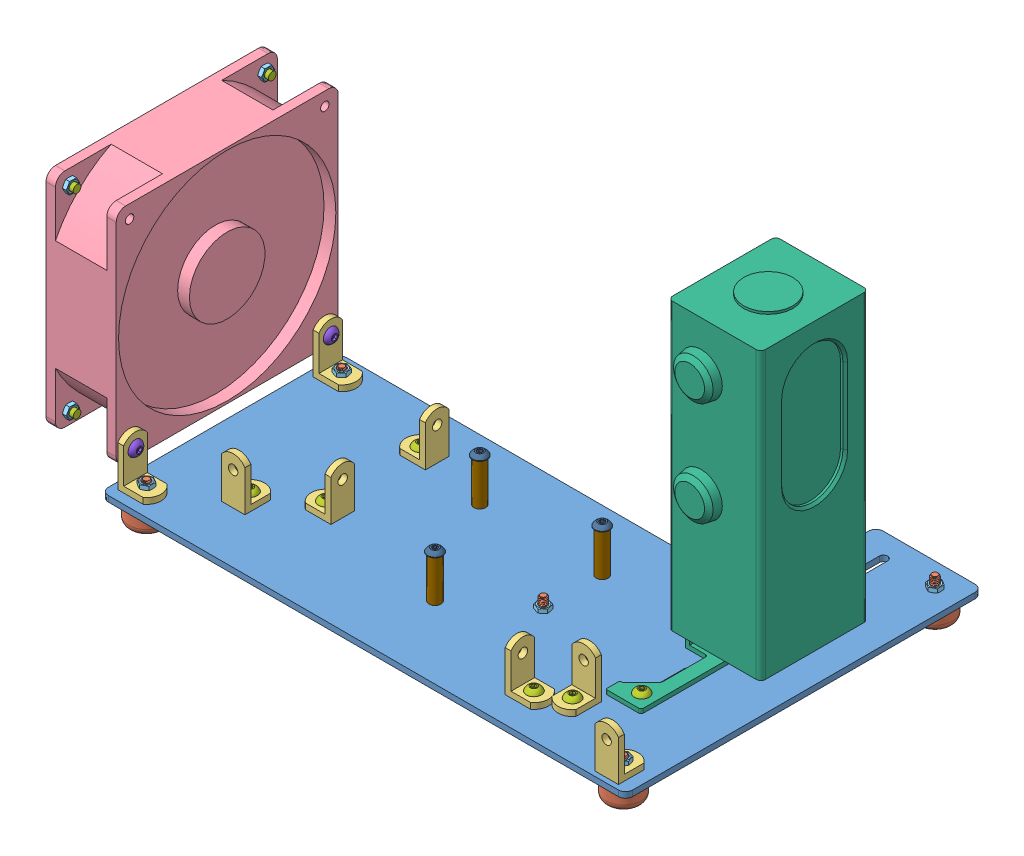
SolidWorks assembly Chiller Plate, configuration Default. Lengths in mm.
Overall size (343.32 202.03 208.02).
58 component instances, 10 part files, 114 mates.
Components (placement in the parent):
- Chiller base plate-1: Chiller base plate [Default] at (-211.7096 17.6388 83.7447) size (281.94 3.07 191.77)
- RUBBER_BUMPER WITH 8-32x375 THREADED STUD-1: RUBBER_BUMPER WITH 8-32x375 THREADED STUD [9541K2] at (-199.0096 17.6388 72.1097) x (-0.837169 0 -0.546944) z (-0.546944 0 0.837169) size (19.05 20.95 19.05)
- RUBBER_BUMPER WITH 8-32x375 THREADED STUD-2: RUBBER_BUMPER WITH 8-32x375 THREADED STUD [9541K2] at (-199.0096 17.6388 -32.8903) x (-0.925243 0 -0.379375) z (-0.379375 0 0.925243) size (19.05 20.95 19.05)
- RUBBER_BUMPER WITH 8-32x375 THREADED STUD-3: RUBBER_BUMPER WITH 8-32x375 THREADED STUD [9541K2] at (57.5304 17.6388 72.1097) x (-0.985271 0 -0.170998) z (-0.170998 0 0.985271) size (19.05 20.95 19.05)
- RUBBER_BUMPER WITH 8-32x375 THREADED STUD-4: RUBBER_BUMPER WITH 8-32x375 THREADED STUD [9541K2] at (57.5304 17.6388 -95.3253) x (-0.997902 0 0.064746) z (0.064746 0 0.997902) size (19.05 20.95 19.05)
- l-bracket_correct-1: l-bracket_correct [Default] at (-208.1028 41.2316 52.9979) x (0 0 -1) z (0 -1 0) size (12.7 16.94 25.35)
- l-bracket_correct-2: l-bracket_correct [Default] at (-208.1028 41.2316 -52.0021) x (0 0 -1) z (0 -1 0) size (12.7 16.94 25.35)
- 120mm_fan-2: 120mm_fan [Default] at (-208.1028 148.004 70.9708) x (0 1 0) z (0 0 1) size (119.38 37.75 119.38)
- S-008-NUT-SS-001_832-SS-Nut-3-32thk-1: S-008-NUT-SS-001_832-SS-Nut-3-32thk [Default] at (-199.0096 23.8872 72.1097) size (6.35 2.38 7.33)
- S-008-NUT-SS-001_832-SS-Nut-3-32thk-2: S-008-NUT-SS-001_832-SS-Nut-3-32thk [Default] at (-199.0096 23.8872 -32.8903) x (0.982082 0 -0.188455) z (0.188455 0 0.982082) size (6.35 2.38 7.33)
- S-008-NUT-SS-001_832-SS-Nut-3-32thk-4: S-008-NUT-SS-001_832-SS-Nut-3-32thk [Default] at (57.5304 20.7122 72.1097) x (0.918365 0 -0.395734) z (0.395734 0 0.918365) size (6.35 2.38 7.33)
- l-bracket_correct-7: l-bracket_correct [Default] at (-8.4588 41.2316 44.3129) x (0 0 -1) z (0 -1 0) size (12.7 16.94 25.35)
- l-bracket_correct-8: l-bracket_correct [Default] at (38.4186 41.2316 81.2029) x (-1 0 0) z (0 -1 0) size (12.7 16.94 25.35)
- S-008-NUT-SS-001_832-SS-Nut-3-32thk-5: S-008-NUT-SS-001_832-SS-Nut-3-32thk [Default] at (57.5304 20.7122 -95.3253) size (6.35 2.38 7.33)
- S-008-NUT-SS-001_832-SS-Nut-3-32thk-6: S-008-NUT-SS-001_832-SS-Nut-3-32thk [Default] at (57.5304 23.8872 72.1097) x (0.965281 0 -0.261214) z (0.261214 0 0.965281) size (6.35 2.38 7.33)
- SamsungFoodChiller-1: SamsungFoodChiller [Default] at (-59.6355 20.7122 23.7904) (suppressed, hidden)
- Pump_Reservoir-1: Pump_Reservoir [Default] at (45.3708 36.5618 -17.865) x (0 0 -1) z (1 0 0) size (120.7 170.79 61.26)
- S-008-038-BTN-H-SS-001-832x3_8-button-head-screw-1: S-008-038-BTN-H-SS-001-832x3_8-button-head-screw [Default] at (29.8444 23.0236 -70.365) size (7.92 11.73 7.92)
- S-008-NUT-SS-001_832-SS-Nut-3-32thk-7: S-008-NUT-SS-001_832-SS-Nut-3-32thk [Default] at (29.8444 15.2575 -70.365) size (6.35 2.38 7.33)
- S-008-038-BTN-H-SS-001-832x3_8-button-head-screw-2: S-008-038-BTN-H-SS-001-832x3_8-button-head-screw [Default] at (29.8444 23.0236 34.635) x (0.982082 0 -0.188455) z (0.188455 0 0.982082) size (7.92 11.73 7.92)
- S-008-NUT-SS-001_832-SS-Nut-3-32thk-8: S-008-NUT-SS-001_832-SS-Nut-3-32thk [Default] at (29.8444 15.2575 34.635) x (0.982082 0 -0.188455) z (0.188455 0 0.982082) size (6.35 2.38 7.33)
- S-008-050-BTN-H-SS-001-832x1_2-button-head-screw-1: S-008-050-BTN-H-SS-001-832x1_2-button-head-screw [Default] at (-204.9278 38.4922 72.1097) x (0 -1 0) z (0 0 1) size (7.92 14.91 7.92)
- S-008-NUT-SS-001_832-SS-Nut-3-32thk-11: S-008-NUT-SS-001_832-SS-Nut-3-32thk [Default] at (-215.5591 38.4922 72.1097) x (0 -0.930301 -0.366796) z (0 -0.366796 0.930301) size (6.35 2.38 7.33)
- S-008-050-BTN-H-SS-001-832x1_2-button-head-screw-2: S-008-050-BTN-H-SS-001-832x1_2-button-head-screw [Default] at (-204.9278 38.4922 -32.8903) x (0 -0.987351 -0.158553) z (0 -0.158553 0.987351) size (7.92 14.91 7.92)
- S-008-NUT-SS-001_832-SS-Nut-3-32thk-13: S-008-NUT-SS-001_832-SS-Nut-3-32thk [Default] at (-215.5591 38.4922 -32.8903) x (0 -0.860377 -0.509658) z (0 -0.509658 0.860377) size (6.35 2.38 7.33)
- RUBBER_BUMPER WITH 8-32x375 THREADED STUD-6: RUBBER_BUMPER WITH 8-32x375 THREADED STUD [9541K2] at (-38.1482 17.6388 19.6097) x (-0.985271 0 -0.170998) z (-0.170998 0 0.985271) size (19.05 20.95 19.05)
- S-008-NUT-SS-001_832-SS-Nut-3-32thk-16: S-008-NUT-SS-001_832-SS-Nut-3-32thk [Default] at (-38.1482 20.7122 19.6097) x (0.309274 0 -0.950973) z (0.950973 0 0.309274) size (6.35 2.38 7.33)
- 008 875ALUM UNTHRD SPACER-2: 008 875ALUM UNTHRD SPACER [92510A468] at (-103.9661 31.8247 -12.0903) x (1 0 0) z (0 -1 0) size (6.35 6.35 22.23)
- 008 875ALUM UNTHRD SPACER-3: 008 875ALUM UNTHRD SPACER [92510A468] at (-38.1482 31.8247 -12.0903) x (1 0 0) z (0 -1 0) size (6.35 6.35 22.23)
- 008 875ALUM UNTHRD SPACER-4: 008 875ALUM UNTHRD SPACER [92510A468] at (-71.0571 31.8247 44.9097) x (1 0 0) z (0 -1 0) size (6.35 6.35 22.23)
- S-008-1125-STD-O-AL-001_832xp1125_standoff_p1125hex-1: S-008-1125-STD-O-AL-001_832xp1125_standoff_p1125hex [92949A820] at (-103.9661 45.622 -12.0903) x (1 0 0) z (0 1 0) size (7.92 7.92 31.31)
- S-008-1125-STD-O-AL-001_832xp1125_standoff_p1125hex-2: S-008-1125-STD-O-AL-001_832xp1125_standoff_p1125hex [92949A820] at (-38.1482 45.622 -12.0903) x (0.982082 0 -0.188455) z (0 1 0) size (7.92 7.92 31.31)
- S-008-1125-STD-O-AL-001_832xp1125_standoff_p1125hex-4: S-008-1125-STD-O-AL-001_832xp1125_standoff_p1125hex [92949A820] at (-71.0571 45.622 44.9097) x (0.918365 0 -0.395734) z (0 1 0) size (7.92 7.92 31.31)
- S-008-NUT-SS-001_832-SS-Nut-3-32thk-17: S-008-NUT-SS-001_832-SS-Nut-3-32thk [Default] at (-71.0571 17.6388 44.9097) x (-0.438446 0 0.898758) z (0.898758 0 0.438446) size (6.35 2.38 7.33)
- S-008-NUT-SS-001_832-SS-Nut-3-32thk-19: S-008-NUT-SS-001_832-SS-Nut-3-32thk [Default] at (-103.9661 17.6388 -12.0903) x (-0.621885 0 0.783109) z (0.783109 0 0.621885) size (6.35 2.38 7.33)
- S-008-NUT-SS-001_832-SS-Nut-3-32thk-21: S-008-NUT-SS-001_832-SS-Nut-3-32thk [Default] at (-38.1482 17.6388 -12.0903) x (-0.78814 0 0.615496) z (0.615496 0 0.78814) size (6.35 2.38 7.33)
- l-bracket_correct-9: l-bracket_correct [Default] at (-134.5444 41.2316 -0.6485) x (0 0 1) z (0 -1 0) size (12.7 16.94 25.35)
- l-bracket_correct-10: l-bracket_correct [Default] at (-134.5444 41.2316 50.1515) x (0 0 1) z (0 -1 0) size (12.7 16.94 25.35)
- l-bracket_correct-12: l-bracket_correct [Default] at (-187.6414 41.2316 56.0079) x (-1 0 0) z (0 -1 0) size (12.7 16.94 25.35)
- l-bracket_correct-14: l-bracket_correct [Default] at (33.4622 41.2316 47.2195) x (1 0 0) z (0 -1 0) size (12.7 16.94 25.35)
- S-008-038-BTN-H-SS-001-832x3_8-button-head-screw-4: S-008-038-BTN-H-SS-001-832x3_8-button-head-screw [Default] at (-245.8528 143.4922 -32.8903) x (0 1 0) z (0 0 1) size (7.92 11.73 7.92)
- S-008-NUT-SS-001_832-SS-Nut-3-32thk-22: S-008-NUT-SS-001_832-SS-Nut-3-32thk [Default] at (-238.3966 143.4922 -32.8903) x (0 1 0) z (0 0 1) size (6.35 2.38 7.33)
- S-008-038-BTN-H-SS-001-832x3_8-button-head-screw-5: S-008-038-BTN-H-SS-001-832x3_8-button-head-screw [Default] at (-245.8528 38.4922 -32.8903) x (0 1 0) z (0 0 1) size (7.92 11.73 7.92)
- S-008-038-BTN-H-SS-001-832x3_8-button-head-screw-6: S-008-038-BTN-H-SS-001-832x3_8-button-head-screw [Default] at (-245.8528 143.4922 72.1097) x (0 1 0) z (0 0 1) size (7.92 11.73 7.92)
- S-008-038-BTN-H-SS-001-832x3_8-button-head-screw-7: S-008-038-BTN-H-SS-001-832x3_8-button-head-screw [Default] at (-245.8528 38.4922 72.1097) x (0 1 0) z (0 0 1) size (7.92 11.73 7.92)
- S-008-NUT-SS-001_832-SS-Nut-3-32thk-23: S-008-NUT-SS-001_832-SS-Nut-3-32thk [Default] at (-238.3966 38.4922 -32.8903) x (0 1 0) z (0 0 1) size (6.35 2.38 7.33)
- S-008-NUT-SS-001_832-SS-Nut-3-32thk-24: S-008-NUT-SS-001_832-SS-Nut-3-32thk [Default] at (-238.3966 143.4922 72.1097) x (0 1 0) z (0 0 1) size (6.35 2.38 7.33)
- S-008-NUT-SS-001_832-SS-Nut-3-32thk-25: S-008-NUT-SS-001_832-SS-Nut-3-32thk [Default] at (-238.3966 38.4922 72.1097) x (0 1 0) z (0 0 1) size (6.35 2.38 7.33)
- S-008-038-BTN-H-SS-001-832x3_8-button-head-screw-8: S-008-038-BTN-H-SS-001-832x3_8-button-head-screw [Default] at (-143.6376 23.8872 31.0397) size (7.92 11.73 7.92)
- S-008-NUT-SS-001_832-SS-Nut-3-32thk-26: S-008-NUT-SS-001_832-SS-Nut-3-32thk [Default] at (-143.6376 15.2575 31.0397) size (6.35 2.38 7.33)
- S-008-038-BTN-H-SS-001-832x3_8-button-head-screw-9: S-008-038-BTN-H-SS-001-832x3_8-button-head-screw [Default] at (-168.5296 23.8872 46.9147) x (0.982082 0 -0.188455) z (0.188455 0 0.982082) size (7.92 11.73 7.92)
- S-008-NUT-SS-001_832-SS-Nut-3-32thk-27: S-008-NUT-SS-001_832-SS-Nut-3-32thk [Default] at (-168.5296 15.2575 46.9147) x (0.982082 0 -0.188455) z (0.188455 0 0.982082) size (6.35 2.38 7.33)
- S-008-038-BTN-H-SS-001-832x3_8-button-head-screw-10: S-008-038-BTN-H-SS-001-832x3_8-button-head-screw [Default] at (-143.6376 23.8872 -19.7603) x (0.918365 0 -0.395734) z (0.395734 0 0.918365) size (7.92 11.73 7.92)
- S-008-NUT-SS-001_832-SS-Nut-3-32thk-29: S-008-NUT-SS-001_832-SS-Nut-3-32thk [Default] at (-143.6376 15.2575 -19.7603) x (0.918365 0 -0.395734) z (0.395734 0 0.918365) size (6.35 2.38 7.33)
- S-008-038-BTN-H-SS-001-832x3_8-button-head-screw-11: S-008-038-BTN-H-SS-001-832x3_8-button-head-screw [Default] at (0.6344 23.8872 63.4247) x (0.8 0 -0.6) z (0.6 0 0.8) size (7.92 11.73 7.92)
- S-008-NUT-SS-001_832-SS-Nut-3-32thk-31: S-008-NUT-SS-001_832-SS-Nut-3-32thk [Default] at (0.6344 15.2575 63.4247) x (0.8 0 -0.6) z (0.6 0 0.8) size (6.35 2.38 7.33)
- S-008-038-BTN-H-SS-001-832x3_8-button-head-screw-12: S-008-038-BTN-H-SS-001-832x3_8-button-head-screw [Default] at (14.3504 23.8872 56.3127) x (0.63358 0 -0.773678) z (0.773678 0 0.63358) size (7.92 11.73 7.92)
- S-008-NUT-SS-001_832-SS-Nut-3-32thk-33: S-008-NUT-SS-001_832-SS-Nut-3-32thk [Default] at (14.3504 15.2575 56.3127) x (0.63358 0 -0.773678) z (0.773678 0 0.63358) size (6.35 2.38 7.33)
Mates (geometry in assembly coordinates):
- Coincident1: coincident anti-aligned: plane of Chiller base plate-1 through (-211.7096 17.6388 83.7447) normal (0 -1 0); plane of RUBBER_BUMPER WITH 8-32x375 THREADED STUD-1 through (-204.9069 17.6388 68.2569) normal (0 1 0)
- Concentric1: concentric anti-aligned: cylinder of Chiller base plate-1 through (-199.0096 20.7122 72.1097) axis (0 1 0) radius 2.2479; circle of RUBBER_BUMPER WITH 8-32x375 THREADED STUD-1
- Coincident2: coincident anti-aligned: plane of Chiller base plate-1 through (-211.7096 17.6388 83.7447) normal (0 -1 0); plane of RUBBER_BUMPER WITH 8-32x375 THREADED STUD-2 through (-205.5273 17.6388 -35.5627) normal (0 1 0)
- Concentric2: concentric anti-aligned: cylinder of Chiller base plate-1 through (-199.0096 20.7122 -32.8903) axis (0 1 0) radius 2.2479; circle of RUBBER_BUMPER WITH 8-32x375 THREADED STUD-2
- Coincident3: coincident anti-aligned: plane of Chiller base plate-1 through (-211.7096 17.6388 83.7447) normal (0 -1 0); plane of RUBBER_BUMPER WITH 8-32x375 THREADED STUD-3 through (50.5899 17.6388 70.9051) normal (0 1 0)
- Concentric3: concentric anti-aligned: cylinder of Chiller base plate-1 through (57.5304 20.7122 72.1097) axis (0 1 0) radius 2.2479; circle of RUBBER_BUMPER WITH 8-32x375 THREADED STUD-3
- Coincident4: coincident anti-aligned: plane of Chiller base plate-1 through (-211.7096 17.6388 83.7447) normal (0 -1 0); plane of RUBBER_BUMPER WITH 8-32x375 THREADED STUD-4 through (50.5009 17.6388 -94.8692) normal (0 1 0)
- Concentric4: concentric anti-aligned: cylinder of Chiller base plate-1 through (57.5304 20.7122 -95.3253) axis (0 1 0) radius 2.2479; circle of RUBBER_BUMPER WITH 8-32x375 THREADED STUD-4
- Coincident6: coincident anti-aligned: plane of Chiller base plate-1 through (-211.7096 20.7122 83.7447) normal (0 1 0); plane of l-bracket_correct-1 through (-204.9278 20.7122 78.4597) normal (0 -1 0)
- Coincident7: coincident anti-aligned: plane of Chiller base plate-1 through (-211.7096 20.7122 83.7447) normal (0 1 0); plane of l-bracket_correct-2 through (-204.9278 20.7122 -26.5403) normal (0 -1 0)
- Concentric5: concentric aligned: circle of Chiller base plate-1; cylinder of l-bracket_correct-2 through (-199.0096 20.7122 -32.8903) axis (0 1 0) radius 2.54
- Concentric6: concentric aligned: circle of Chiller base plate-1; cylinder of l-bracket_correct-1 through (-199.0096 20.7122 72.1097) axis (0 1 0) radius 2.54
- Parallel1: parallel aligned: plane of Chiller base plate-1 through (-211.7096 20.7122 83.7447) normal (-1 0 0); plane of l-bracket_correct-1 through (-208.1028 41.2316 52.9979) normal (-1 0 0)
- Parallel2: parallel aligned: plane of Chiller base plate-1 through (-211.7096 20.7122 83.7447) normal (-1 0 0); plane of l-bracket_correct-2 through (-208.1028 41.2316 -52.0021) normal (-1 0 0)
- Concentric13: concentric anti-aligned: circle of l-bracket_correct-1; cylinder of S-008-NUT-SS-001_832-SS-Nut-3-32thk-1 through (-199.0096 26.2684 72.1097) axis (0 -1 0) radius 2.1828
- Coincident16: coincident anti-aligned: plane of l-bracket_correct-1 through (-191.1356 23.8872 78.4597) normal (0 1 0); plane of S-008-NUT-SS-001_832-SS-Nut-3-32thk-1 through (-199.0096 23.8872 72.1097) normal (0 -1 0)
- Concentric14: concentric anti-aligned: cylinder of l-bracket_correct-2 through (-199.0096 20.7122 -32.8903) axis (0 1 0) radius 2.54; cylinder of S-008-NUT-SS-001_832-SS-Nut-3-32thk-2 through (-199.0096 26.2684 -32.8903) axis (0 -1 0) radius 2.1828
- Coincident17: coincident anti-aligned: plane of l-bracket_correct-2 through (-191.1356 23.8872 -26.5403) normal (0 1 0); plane of S-008-NUT-SS-001_832-SS-Nut-3-32thk-2 through (-199.0096 23.8872 -32.8903) normal (0 -1 0)
- Concentric15: concentric anti-aligned: cylinder of Chiller base plate-1 through (57.5304 20.7122 72.1097) axis (0 1 0) radius 2.2479; cylinder of S-008-NUT-SS-001_832-SS-Nut-3-32thk-4 through (57.5304 23.0934 72.1097) axis (0 -1 0) radius 2.1828
- Coincident18: coincident anti-aligned: plane of Chiller base plate-1 through (-211.7096 20.7122 83.7447) normal (0 1 0); plane of S-008-NUT-SS-001_832-SS-Nut-3-32thk-4 through (57.5304 20.7122 72.1097) normal (0 -1 0)
- Coincident23: coincident anti-aligned: plane of Chiller base plate-1 through (-211.7096 20.7122 83.7447) normal (0 1 0); plane of l-bracket_correct-8 through (63.8804 20.7122 78.0279) normal (0 -1 0)
- Coincident24: coincident anti-aligned: plane of Chiller base plate-1 through (-211.7096 20.7122 83.7447) normal (0 1 0); plane of l-bracket_correct-7 through (-5.2838 20.7122 69.7747) normal (0 -1 0)
- Concentric18: concentric anti-aligned: cylinder of RUBBER_BUMPER WITH 8-32x375 THREADED STUD-3 through (57.5304 6.5263 72.1097) axis (0 -1 0) radius 9.525; cylinder of l-bracket_correct-8 through (57.5304 20.7122 72.1097) axis (0 1 0) radius 2.54
- Parallel6: parallel aligned: plane of Chiller base plate-1 through (-211.7096 20.7122 83.7447) normal (0 0 1); plane of l-bracket_correct-8 through (38.4186 41.2316 81.2029) normal (0 0 1)
- Concentric19: concentric aligned: cylinder of Chiller base plate-1 through (0.6344 20.7122 63.4247) axis (0 1 0) radius 2.2479; cylinder of l-bracket_correct-7 through (0.6344 20.7122 63.4247) axis (0 1 0) radius 2.54
- Concentric20: concentric anti-aligned: cylinder of l-bracket_correct-1 through (-208.1028 38.4922 72.1097) axis (1 0 0) radius 2.54; cylinder of 120mm_fan-2 through (-208.1028 38.4922 72.1097) axis (-1 0 0) radius 2.286
- Parallel8: parallel anti-aligned: cylinder of l-bracket_correct-2 through (-208.1028 38.4922 -32.8903) axis (1 0 0) radius 2.54; cylinder of 120mm_fan-2 through (-208.1028 38.4922 -32.8903) axis (-1 0 0) radius 2.286
- Coincident25: coincident anti-aligned: plane of Chiller base plate-1 through (-211.7096 20.7122 83.7447) normal (0 1 0); plane of S-008-NUT-SS-001_832-SS-Nut-3-32thk-5 through (57.5304 20.7122 -95.3253) normal (0 -1 0)
- Concentric21: concentric anti-aligned: cylinder of Chiller base plate-1 through (57.5304 20.7122 -95.3253) axis (0 1 0) radius 2.2479; cylinder of S-008-NUT-SS-001_832-SS-Nut-3-32thk-5 through (57.5304 23.0934 -95.3253) axis (0 -1 0) radius 2.1828
- Concentric22: concentric aligned: cylinder of S-008-NUT-SS-001_832-SS-Nut-3-32thk-4 through (57.5304 23.0934 72.1097) axis (0 -1 0) radius 2.1828; cylinder of S-008-NUT-SS-001_832-SS-Nut-3-32thk-6 through (57.5304 26.2684 72.1097) axis (0 -1 0) radius 2.1828
- Coincident26: coincident anti-aligned: plane of l-bracket_correct-8 through (63.8804 23.8872 64.2357) normal (0 1 0); plane of S-008-NUT-SS-001_832-SS-Nut-3-32thk-6 through (57.5304 23.8872 72.1097) normal (0 -1 0)
- Coincident27: coincident anti-aligned: plane of l-bracket_correct-1 through (-208.1028 41.2316 52.9979) normal (-1 0 0); plane of 120mm_fan-2 through (-208.1028 148.004 70.9708) normal (1 0 0)
- Concentric23: concentric anti-aligned: cylinder of l-bracket_correct-2 through (-208.1028 38.4922 -32.8903) axis (1 0 0) radius 2.54; cylinder of 120mm_fan-2 through (-208.1028 38.4922 -32.8903) axis (-1 0 0) radius 2.286
- Concentric24: concentric anti-aligned: cylinder of Chiller base plate-1 through (-103.9661 20.7122 -12.0903) axis (0 1 0) radius 2.2479; cylinder of ? through (-103.9661 11.8561 -12.0903) axis (0 -1 0) radius 3.3
- Concentric25: concentric anti-aligned: cylinder of Chiller base plate-1 through (-38.1482 20.7122 -12.0903) axis (0 1 0) radius 2.2479; cylinder of ? through (-38.1482 11.8561 -12.0903) axis (0 -1 0) radius 3.3
- Coincident28: coincident anti-aligned: plane of Chiller base plate-1 through (-211.7096 20.7122 83.7447) normal (0 1 0); plane of ? through (-28.1482 20.7122 -12.0903) normal (0 -1 0)
- Coincident29: coincident anti-aligned: plane of Chiller base plate-1 through (-211.7096 20.7122 83.7447) normal (0 1 0); plane of Pump_Reservoir-1 through (36.0744 20.7122 -19.135) normal (0 -1 0)
- Concentric28: concentric aligned: cylinder of Pump_Reservoir-1 through (29.8444 190.2328 -70.365) axis (0 -1 0) radius 2.5; cylinder of S-008-038-BTN-H-SS-001-832x3_8-button-head-screw-1 through (29.8444 13.4986 -70.365) axis (0 -1 0) radius 2.0828
- Coincident32: coincident anti-aligned: plane of Pump_Reservoir-1 through (36.0744 23.0236 -19.135) normal (0 1 0); plane of S-008-038-BTN-H-SS-001-832x3_8-button-head-screw-1 through (27.7616 23.0236 -70.365) normal (0 -1 0)
- Coincident33: coincident anti-aligned: plane of Chiller base plate-1 through (-211.7096 17.6388 83.7447) normal (0 -1 0); plane of S-008-NUT-SS-001_832-SS-Nut-3-32thk-7 through (29.8444 17.6388 -70.365) normal (0 1 0)
- Concentric29: concentric aligned: cylinder of S-008-038-BTN-H-SS-001-832x3_8-button-head-screw-1 through (29.8444 13.4986 -70.365) axis (0 -1 0) radius 2.0828; cylinder of S-008-NUT-SS-001_832-SS-Nut-3-32thk-7 through (29.8444 17.6388 -70.365) axis (0 -1 0) radius 2.1828
- Concentric30: concentric aligned: cylinder of S-008-038-BTN-H-SS-001-832x3_8-button-head-screw-2 through (29.8444 13.4986 34.635) axis (0 -1 0) radius 2.0828; cylinder of S-008-NUT-SS-001_832-SS-Nut-3-32thk-8 through (29.8444 17.6388 34.635) axis (0 -1 0) radius 2.1828
- Concentric31: concentric aligned: cylinder of Pump_Reservoir-1 through (29.8444 190.2328 34.635) axis (0 -1 0) radius 2.5; cylinder of S-008-038-BTN-H-SS-001-832x3_8-button-head-screw-2 through (29.8444 13.4986 34.635) axis (0 -1 0) radius 2.0828
- Coincident34: coincident anti-aligned: plane of Pump_Reservoir-1 through (36.0744 23.0236 -19.135) normal (0 1 0); plane of S-008-038-BTN-H-SS-001-832x3_8-button-head-screw-2 through (27.7989 23.0236 35.0276) normal (0 -1 0)
- Coincident35: coincident anti-aligned: plane of Chiller base plate-1 through (-211.7096 17.6388 83.7447) normal (0 -1 0); plane of S-008-NUT-SS-001_832-SS-Nut-3-32thk-8 through (29.8444 17.6388 34.635) normal (0 1 0)
- Concentric33: concentric anti-aligned: cylinder of l-bracket_correct-1 through (-208.1028 38.4922 72.1097) axis (1 0 0) radius 2.54; cylinder of S-008-050-BTN-H-SS-001-832x1_2-button-head-screw-1 through (-217.6278 38.4922 72.1097) axis (-1 0 0) radius 2.0828
- Coincident36: coincident anti-aligned: plane of l-bracket_correct-1 through (-204.9278 41.2316 52.9979) normal (1 0 0); plane of S-008-050-BTN-H-SS-001-832x1_2-button-head-screw-1 through (-204.9278 40.575 72.1097) normal (-1 0 0)
- Coincident38: coincident anti-aligned: plane of 120mm_fan-2 through (-213.1778 90.9922 19.6097) normal (-1 0 0); plane of S-008-NUT-SS-001_832-SS-Nut-3-32thk-11 through (-213.1778 38.4922 72.1097) normal (1 0 0)
- Concentric34: concentric aligned: cylinder of S-008-050-BTN-H-SS-001-832x1_2-button-head-screw-1 through (-217.6278 38.4922 72.1097) axis (-1 0 0) radius 2.0828; cylinder of S-008-NUT-SS-001_832-SS-Nut-3-32thk-11 through (-213.1778 38.4922 72.1097) axis (-1 0 0) radius 2.1828
- Concentric35: concentric aligned: cylinder of S-008-050-BTN-H-SS-001-832x1_2-button-head-screw-2 through (-217.6278 38.4922 -32.8903) axis (-1 0 0) radius 2.0828; cylinder of S-008-NUT-SS-001_832-SS-Nut-3-32thk-13 through (-213.1778 38.4922 -32.8903) axis (-1 0 0) radius 2.1828
- Concentric36: concentric anti-aligned: cylinder of l-bracket_correct-2 through (-208.1028 38.4922 -32.8903) axis (1 0 0) radius 2.54; cylinder of S-008-050-BTN-H-SS-001-832x1_2-button-head-screw-2 through (-217.6278 38.4922 -32.8903) axis (-1 0 0) radius 2.0828
- Coincident39: coincident anti-aligned: plane of l-bracket_correct-2 through (-204.9278 41.2316 -52.0021) normal (1 0 0); plane of S-008-050-BTN-H-SS-001-832x1_2-button-head-screw-2 through (-204.9278 40.5486 -32.5601) normal (-1 0 0)
- Coincident40: coincident anti-aligned: plane of 120mm_fan-2 through (-213.1778 90.9922 19.6097) normal (-1 0 0); plane of S-008-NUT-SS-001_832-SS-Nut-3-32thk-13 through (-213.1778 38.4922 -32.8903) normal (1 0 0)
- Slot1: slot anti-aligned: cylinder of Chiller base plate-1 through (29.8444 17.6388 -69.9253) axis (0 1 0) radius 2.2479; cylinder of S-008-038-BTN-H-SS-001-832x3_8-button-head-screw-1 through (29.8444 13.4986 -70.365) axis (0 -1 0) radius 2.0828; cylinder of Chiller base plate-1 through (29.8444 17.6388 -95.3253) axis (0 1 0) radius 2.2479
- Slot2: slot anti-aligned: cylinder of Chiller base plate-1 through (29.8444 17.6388 35.0747) axis (0 1 0) radius 2.2479; cylinder of S-008-038-BTN-H-SS-001-832x3_8-button-head-screw-2 through (29.8444 13.4986 34.635) axis (0 -1 0) radius 2.0828; cylinder of Chiller base plate-1 through (29.8444 17.6388 9.6747) axis (0 1 0) radius 2.2479
- Coincident42: coincident anti-aligned: plane of Chiller base plate-1 through (-211.7096 17.6388 83.7447) normal (0 -1 0); plane of RUBBER_BUMPER WITH 8-32x375 THREADED STUD-6 through (-45.0887 17.6388 18.4051) normal (0 1 0)
- Concentric39: concentric aligned: cylinder of Chiller base plate-1 through (-38.1482 20.7122 19.6097) axis (0 1 0) radius 2.2479; circle of RUBBER_BUMPER WITH 8-32x375 THREADED STUD-6
- Concentric40: concentric anti-aligned: cylinder of Chiller base plate-1 through (-38.1482 20.7122 19.6097) axis (0 1 0) radius 2.2479; cylinder of S-008-NUT-SS-001_832-SS-Nut-3-32thk-16 through (-38.1482 23.0934 19.6097) axis (0 -1 0) radius 2.1828
- Coincident43: coincident anti-aligned: plane of Chiller base plate-1 through (-211.7096 20.7122 83.7447) normal (0 1 0); plane of S-008-NUT-SS-001_832-SS-Nut-3-32thk-16 through (-38.1482 20.7122 19.6097) normal (0 -1 0)
- Concentric41: concentric anti-aligned: cylinder of ? through (-103.9661 11.8561 -12.0903) axis (0 -1 0) radius 3.3; cylinder of 008 875ALUM UNTHRD SPACER-2 through (-103.9661 20.7122 -12.0903) axis (0 1 0) radius 3.175
- Coincident44: coincident anti-aligned: plane of Chiller base plate-1 through (-211.7096 20.7122 83.7447) normal (0 1 0); plane of 008 875ALUM UNTHRD SPACER-2 through (-103.9661 20.7122 -12.0903) normal (0 -1 0)
- Concentric43: concentric anti-aligned: cylinder of ? through (-71.0571 11.8561 44.9097) axis (0 -1 0) radius 3.3; cylinder of 008 875ALUM UNTHRD SPACER-4 through (-71.0571 20.7122 44.9097) axis (0 1 0) radius 3.175
- Coincident45: coincident anti-aligned: plane of Chiller base plate-1 through (-211.7096 20.7122 83.7447) normal (0 1 0); circle of 008 875ALUM UNTHRD SPACER-4
- Concentric44: concentric anti-aligned: cylinder of ? through (-38.1482 11.8561 -12.0903) axis (0 -1 0) radius 3.3; cylinder of 008 875ALUM UNTHRD SPACER-3 through (-38.1482 20.7122 -12.0903) axis (0 1 0) radius 3.175
- Coincident46: coincident anti-aligned: plane of Chiller base plate-1 through (-211.7096 20.7122 83.7447) normal (0 1 0); plane of 008 875ALUM UNTHRD SPACER-3 through (-38.1482 20.7122 -12.0903) normal (0 -1 0)
- Concentric46: concentric aligned: cylinder of 008 875ALUM UNTHRD SPACER-2 through (-103.9661 20.7122 -12.0903) axis (0 1 0) radius 2.1082; cylinder of S-008-1125-STD-O-AL-001_832xp1125_standoff_p1125hex-1 through (-103.9661 45.622 -12.0903) axis (0 1 0) radius 3.9624
- Coincident48: coincident anti-aligned: plane of ? through (-100.6661 43.4122 -12.0903) normal (0 1 0); plane of S-008-1125-STD-O-AL-001_832xp1125_standoff_p1125hex-1 through (-103.9661 43.4122 -8.1279) normal (0 -1 0)
- Concentric47: concentric aligned: cylinder of 008 875ALUM UNTHRD SPACER-3 through (-38.1482 20.7122 -12.0903) axis (0 1 0) radius 2.1082; cylinder of S-008-1125-STD-O-AL-001_832xp1125_standoff_p1125hex-2 through (-38.1482 45.622 -12.0903) axis (0 1 0) radius 3.9624
- Coincident49: coincident anti-aligned: plane of ? through (-34.8482 43.4122 -12.0903) normal (0 1 0); plane of S-008-1125-STD-O-AL-001_832xp1125_standoff_p1125hex-2 through (-37.4014 43.4122 -8.1989) normal (0 -1 0)
- Concentric48: concentric aligned: cylinder of 008 875ALUM UNTHRD SPACER-4 through (-71.0571 20.7122 44.9097) axis (0 1 0) radius 2.1082; cylinder of S-008-1125-STD-O-AL-001_832xp1125_standoff_p1125hex-4 through (-71.0571 45.622 44.9097) axis (0 1 0) radius 3.9624
- Coincident50: coincident anti-aligned: plane of ? through (-67.7571 43.4122 44.9097) normal (0 1 0); plane of S-008-1125-STD-O-AL-001_832xp1125_standoff_p1125hex-4 through (-69.4891 43.4122 48.5486) normal (0 -1 0)
- Concentric49: concentric aligned: cylinder of Chiller base plate-1 through (-71.0571 20.7122 44.9097) axis (0 1 0) radius 2.2479; cylinder of S-008-NUT-SS-001_832-SS-Nut-3-32thk-17 through (-71.0571 15.2575 44.9097) axis (0 1 0) radius 2.1828
- Coincident51: coincident anti-aligned: plane of Chiller base plate-1 through (-211.7096 17.6388 83.7447) normal (0 -1 0); plane of S-008-NUT-SS-001_832-SS-Nut-3-32thk-17 through (-71.0571 17.6388 44.9097) normal (0 1 0)
- Concentric50: concentric aligned: cylinder of Chiller base plate-1 through (-103.9661 20.7122 -12.0903) axis (0 1 0) radius 2.2479; cylinder of S-008-NUT-SS-001_832-SS-Nut-3-32thk-19 through (-103.9661 15.2575 -12.0903) axis (0 1 0) radius 2.1828
- Coincident52: coincident anti-aligned: plane of Chiller base plate-1 through (-211.7096 17.6388 83.7447) normal (0 -1 0); plane of S-008-NUT-SS-001_832-SS-Nut-3-32thk-19 through (-103.9661 17.6388 -12.0903) normal (0 1 0)
- Concentric51: concentric aligned: cylinder of Chiller base plate-1 through (-38.1482 20.7122 -12.0903) axis (0 1 0) radius 2.2479; cylinder of S-008-NUT-SS-001_832-SS-Nut-3-32thk-21 through (-38.1482 15.2575 -12.0903) axis (0 1 0) radius 2.1828
- Coincident53: coincident anti-aligned: plane of Chiller base plate-1 through (-211.7096 17.6388 83.7447) normal (0 -1 0); plane of S-008-NUT-SS-001_832-SS-Nut-3-32thk-21 through (-38.1482 17.6388 -12.0903) normal (0 1 0)
- Parallel9: parallel anti-aligned: plane of l-bracket_correct-7 through (-5.2838 41.2316 44.3129) normal (1 0 0); plane of ? through (-5.2972 95.7471 70.3092) normal (-1 0 0)
- Coincident55: coincident anti-aligned: plane of Chiller base plate-1 through (-211.7096 20.7122 83.7447) normal (0 1 0); plane of l-bracket_correct-9 through (-137.7194 20.7122 -26.1103) normal (0 -1 0)
- Concentric52: concentric aligned: cylinder of Chiller base plate-1 through (-143.6376 20.7122 -19.7603) axis (0 1 0) radius 2.2479; cylinder of l-bracket_correct-9 through (-143.6376 20.7122 -19.7603) axis (0 1 0) radius 2.54
- Parallel10: parallel: plane of ? through (-131.2669 39.2471 30.0329) normal (1 0 0); plane of l-bracket_correct-9 through (-137.7194 41.2316 -0.6485) normal (-1 0 0)
- Coincident56: coincident anti-aligned: plane of Chiller base plate-1 through (-211.7096 20.7122 83.7447) normal (0 1 0); plane of l-bracket_correct-10 through (-137.7194 20.7122 24.6897) normal (0 -1 0)
- Concentric53: concentric aligned: cylinder of Chiller base plate-1 through (-143.6376 20.7122 31.0397) axis (0 1 0) radius 2.2479; cylinder of l-bracket_correct-10 through (-143.6376 20.7122 31.0397) axis (0 1 0) radius 2.54
- Parallel11: parallel: plane of ? through (-131.2669 39.2471 30.0329) normal (1 0 0); plane of l-bracket_correct-10 through (-137.7194 41.2316 50.1515) normal (-1 0 0)
- Coincident58: coincident anti-aligned: plane of Chiller base plate-1 through (-211.7096 20.7122 83.7447) normal (0 1 0); plane of l-bracket_correct-12 through (-162.1796 20.7122 52.8329) normal (0 -1 0)
- Concentric54: concentric aligned: cylinder of Chiller base plate-1 through (-168.5296 20.7122 46.9147) axis (0 1 0) radius 2.2479; cylinder of l-bracket_correct-12 through (-168.5296 20.7122 46.9147) axis (0 1 0) radius 2.54
- Parallel12: parallel anti-aligned: plane of Chiller base plate-1 through (-211.7096 20.7122 83.7447) normal (0 0 1); plane of l-bracket_correct-12 through (-187.6414 41.2316 52.8329) normal (0 0 -1)
- Coincident60: coincident anti-aligned: plane of Chiller base plate-1 through (-211.7096 20.7122 83.7447) normal (0 1 0); plane of l-bracket_correct-14 through (8.0004 20.7122 50.3945) normal (0 -1 0)
- Concentric55: concentric aligned: cylinder of Chiller base plate-1 through (14.3504 20.7122 56.3127) axis (0 1 0) radius 2.2479; cylinder of l-bracket_correct-14 through (14.3504 20.7122 56.3127) axis (0 1 0) radius 2.54
- Parallel13: parallel anti-aligned: plane of ? through (27.1028 28.2471 50.3092) normal (0 0 -1); plane of l-bracket_correct-14 through (33.4622 41.2316 50.3945) normal (0 0 1)
- Concentric56: concentric anti-aligned: cylinder of 120mm_fan-2 through (-208.1028 143.4922 -32.8903) axis (-1 0 0) radius 2.286; cylinder of S-008-038-BTN-H-SS-001-832x3_8-button-head-screw-4 through (-236.3278 143.4922 -32.8903) axis (1 0 0) radius 2.0828
- Coincident61: coincident anti-aligned: plane of 120mm_fan-2 through (-245.8528 148.004 70.9708) normal (-1 0 0); plane of S-008-038-BTN-H-SS-001-832x3_8-button-head-screw-4 through (-245.8528 141.4094 -32.8903) normal (1 0 0)
- Coincident62: coincident anti-aligned: plane of 120mm_fan-2 through (-240.7778 90.9922 19.6097) normal (1 0 0); plane of S-008-NUT-SS-001_832-SS-Nut-3-32thk-22 through (-240.7778 143.4922 -32.8903) normal (-1 0 0)
- Concentric57: concentric aligned: cylinder of S-008-038-BTN-H-SS-001-832x3_8-button-head-screw-4 through (-236.3278 143.4922 -32.8903) axis (1 0 0) radius 2.0828; cylinder of S-008-NUT-SS-001_832-SS-Nut-3-32thk-22 through (-240.7778 143.4922 -32.8903) axis (1 0 0) radius 2.1828
- Concentric58: concentric anti-aligned: cylinder of l-bracket_correct-10 through (-143.6376 20.7122 31.0397) axis (0 1 0) radius 2.54; cylinder of S-008-038-BTN-H-SS-001-832x3_8-button-head-screw-8 through (-143.6376 14.3622 31.0397) axis (0 -1 0) radius 2.0828
- Coincident63: coincident anti-aligned: plane of l-bracket_correct-10 through (-151.5116 23.8872 24.6897) normal (0 1 0); plane of S-008-038-BTN-H-SS-001-832x3_8-button-head-screw-8 through (-145.7204 23.8872 31.0397) normal (0 -1 0)
- Concentric60: concentric aligned: cylinder of S-008-038-BTN-H-SS-001-832x3_8-button-head-screw-8 through (-143.6376 14.3622 31.0397) axis (0 -1 0) radius 2.0828; cylinder of S-008-NUT-SS-001_832-SS-Nut-3-32thk-26 through (-143.6376 17.6388 31.0397) axis (0 -1 0) radius 2.1828
- Coincident65: coincident anti-aligned: plane of Chiller base plate-1 through (-211.7096 17.6388 83.7447) normal (0 -1 0); plane of S-008-NUT-SS-001_832-SS-Nut-3-32thk-26 through (-143.6376 17.6388 31.0397) normal (0 1 0)
- Concentric61: concentric aligned: cylinder of S-008-038-BTN-H-SS-001-832x3_8-button-head-screw-9 through (-168.5296 14.3622 46.9147) axis (0 -1 0) radius 2.0828; cylinder of S-008-NUT-SS-001_832-SS-Nut-3-32thk-27 through (-168.5296 17.6388 46.9147) axis (0 -1 0) radius 2.1828
- Concentric62: concentric anti-aligned: cylinder of l-bracket_correct-12 through (-168.5296 20.7122 46.9147) axis (0 1 0) radius 2.54; cylinder of S-008-038-BTN-H-SS-001-832x3_8-button-head-screw-9 through (-168.5296 14.3622 46.9147) axis (0 -1 0) radius 2.0828
- Coincident66: coincident anti-aligned: plane of l-bracket_correct-12 through (-162.1796 23.8872 39.0407) normal (0 1 0); plane of S-008-038-BTN-H-SS-001-832x3_8-button-head-screw-9 through (-170.5751 23.8872 47.3072) normal (0 -1 0)
- Coincident67: coincident anti-aligned: plane of Chiller base plate-1 through (-211.7096 17.6388 83.7447) normal (0 -1 0); plane of S-008-NUT-SS-001_832-SS-Nut-3-32thk-27 through (-168.5296 17.6388 46.9147) normal (0 1 0)
- Concentric64: concentric aligned: cylinder of S-008-038-BTN-H-SS-001-832x3_8-button-head-screw-10 through (-143.6376 14.3622 -19.7603) axis (0 -1 0) radius 2.0828; cylinder of S-008-NUT-SS-001_832-SS-Nut-3-32thk-29 through (-143.6376 17.6388 -19.7603) axis (0 -1 0) radius 2.1828
- Concentric65: concentric anti-aligned: cylinder of l-bracket_correct-9 through (-143.6376 20.7122 -19.7603) axis (0 1 0) radius 2.54; cylinder of S-008-038-BTN-H-SS-001-832x3_8-button-head-screw-10 through (-143.6376 14.3622 -19.7603) axis (0 -1 0) radius 2.0828
- Coincident68: coincident anti-aligned: plane of l-bracket_correct-9 through (-151.5116 23.8872 -26.1103) normal (0 1 0); plane of S-008-038-BTN-H-SS-001-832x3_8-button-head-screw-10 through (-145.5504 23.8872 -18.9361) normal (0 -1 0)
- Coincident69: coincident anti-aligned: plane of Chiller base plate-1 through (-211.7096 17.6388 83.7447) normal (0 -1 0); plane of S-008-NUT-SS-001_832-SS-Nut-3-32thk-29 through (-143.6376 17.6388 -19.7603) normal (0 1 0)
- Concentric67: concentric aligned: cylinder of S-008-038-BTN-H-SS-001-832x3_8-button-head-screw-11 through (0.6344 14.3622 63.4247) axis (0 -1 0) radius 2.0828; cylinder of S-008-NUT-SS-001_832-SS-Nut-3-32thk-31 through (0.6344 17.6388 63.4247) axis (0 -1 0) radius 2.1828
- Concentric68: concentric anti-aligned: cylinder of l-bracket_correct-7 through (0.6344 20.7122 63.4247) axis (0 1 0) radius 2.54; cylinder of S-008-038-BTN-H-SS-001-832x3_8-button-head-screw-11 through (0.6344 14.3622 63.4247) axis (0 -1 0) radius 2.0828
- Coincident70: coincident anti-aligned: plane of l-bracket_correct-7 through (8.5084 23.8872 69.7747) normal (0 1 0); plane of S-008-038-BTN-H-SS-001-832x3_8-button-head-screw-11 through (-1.0319 23.8872 64.6744) normal (0 -1 0)
- Coincident71: coincident anti-aligned: plane of Chiller base plate-1 through (-211.7096 17.6388 83.7447) normal (0 -1 0); plane of S-008-NUT-SS-001_832-SS-Nut-3-32thk-31 through (0.6344 17.6388 63.4247) normal (0 1 0)
- Concentric70: concentric aligned: cylinder of S-008-038-BTN-H-SS-001-832x3_8-button-head-screw-12 through (14.3504 14.3622 56.3127) axis (0 -1 0) radius 2.0828; cylinder of S-008-NUT-SS-001_832-SS-Nut-3-32thk-33 through (14.3504 17.6388 56.3127) axis (0 -1 0) radius 2.1828
- Concentric71: concentric anti-aligned: cylinder of l-bracket_correct-14 through (14.3504 20.7122 56.3127) axis (0 1 0) radius 2.54; cylinder of S-008-038-BTN-H-SS-001-832x3_8-button-head-screw-12 through (14.3504 14.3622 56.3127) axis (0 -1 0) radius 2.0828
- Coincident72: coincident anti-aligned: plane of l-bracket_correct-14 through (8.0004 23.8872 64.1867) normal (0 1 0); plane of S-008-038-BTN-H-SS-001-832x3_8-button-head-screw-12 through (13.0308 23.8872 57.9241) normal (0 -1 0)
- Coincident73: coincident anti-aligned: plane of Chiller base plate-1 through (-211.7096 17.6388 83.7447) normal (0 -1 0); plane of S-008-NUT-SS-001_832-SS-Nut-3-32thk-33 through (14.3504 17.6388 56.3127) normal (0 1 0)
